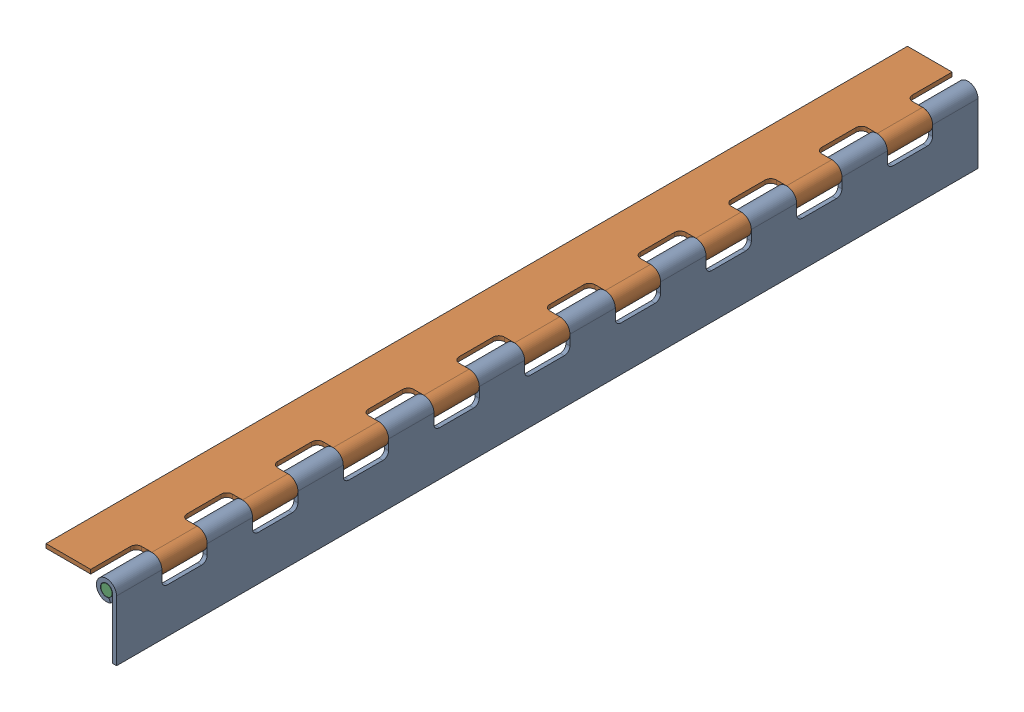
SolidWorks assembly FE-00004-03_, configuration Default. Lengths in mm.
Overall size (39.53 39.53 482.6).
3 component instances, 3 part files, 0 mates.
Components (placement in the parent):
- FE-00004-03A_-1: FE-00004-03A_ [Default] at origin size (11.3 39.53 482.6)
- FE-00004-03B_-1: FE-00004-03B_ [Default] at (-28.5213 28.5213 482.6) x (0 1 0) z (0 0 -1) size (11.3 39.53 482.6)
- FE-00004-03C_-1: FE-00004-03C_ [Default] at (9.0309 7.3635 0) size (6.35 6.35 482.6)
